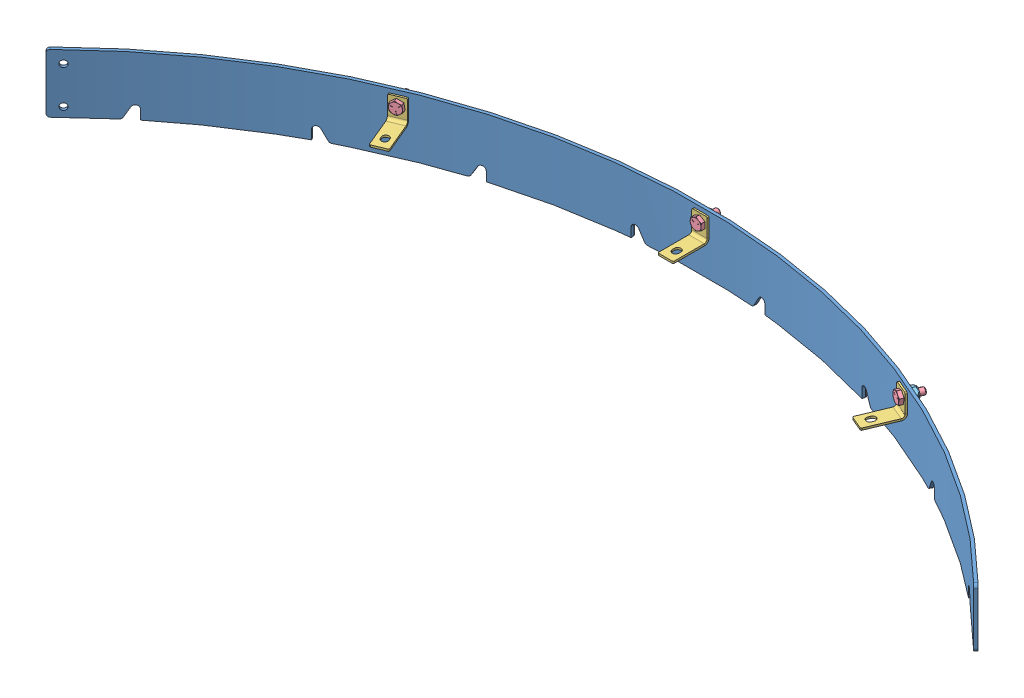
SolidWorks assembly GE-22420, configuration Alt. Lengths in mm.
Overall size (957 60.34 213.8).
14 component instances, 5 part files, 49 mates.
Components (placement in the parent):
- GE-22421-1: GE-22421 [Default] at origin
- tape_VISIONTARGET-1: tape_VISIONTARGET [Default] x (0.630073 0 0.776536) z (-0.776536 0 0.630073)
- tape_VISIONTARGET-2: tape_VISIONTARGET [Default] x (0.285774 0 0.958297) z (-0.958297 0 0.285774)
- tape_VISIONTARGET-3: tape_VISIONTARGET [Default] x (-0.101843 0 0.9948) z (-0.9948 0 -0.101843)
- tape_VISIONTARGET-4: tape_VISIONTARGET [Default] x (-0.474023 0 0.880512) z (-0.880512 0 -0.474023)
- GE-22422-1: GE-22422 [Default] at (-265.7747 33.7439 -617.9649) x (0.92324 0 -0.384223) z (0.384223 0 0.92324)
- GE-22422-2: GE-22422 [Default] at (-7.9375 33.7439 -672.6469) x (1 0 0) z (0 0 1)
- GE-22422-3: GE-22422 [Default] at (251.1183 33.7439 -624.0645) x (0.92324 0 0.384223) z (-0.384223 0 0.92324)
- hex_.25_20_0.75-1: hex_.25_20_0.75 [Default] at (261.3438 47.625 -627.9765) x (0.384223 0 -0.92324) z (0.569796 0.78683 0.237131)
- nylock_.25_20-1: nylock_.25_20 [Default] at (260.4505 47.625 -625.83) x (0.908619 -0.177267 0.378138) z (0.16366 0.984163 0.06811)
- hex_.25_20_0.75-2: hex_.25_20_0.75 [Default] at (0 47.625 -680.1875) x (0 0 -1) z (0.514136 0.857709 0)
- nylock_.25_20-2: nylock_.25_20 [Default] at (0 47.625 -677.8625) x (0.998592 -0.053043 0) z (0.053043 0.998592 0)
- hex_.25_20_0.75-4: hex_.25_20_0.75 [Default] at (-261.3438 47.625 -627.9765) x (-0.384223 0 -0.92324) z (0.341542 0.929056 -0.142139)
- nylock_.25_20-4: nylock_.25_20 [Default] at (-260.4504 47.625 -625.83) x (0.917862 0.107779 -0.381985) z (-0.099506 0.994175 0.041411)
Mates (geometry in assembly coordinates):
- Concentric2: concentric anti-aligned: cylinder of GE-22421-1 through (0 -1034.6728 0) axis (0 1 0) radius 677.8625; cylinder of visionTapeforRing_exoV4-1 through (0 0 0) axis (0 -1 0) radius 677.8625
- Coincident1: coincident aligned: plane of visionRing_exoV4-1 through (0 0 0) normal (0 -1 0); plane of visionTapeforRing_exoV4-1 through (0 0 0) normal (0 -1 0)
- Concentric3: concentric anti-aligned: cylinder of GE-22421-1 through (0 -1034.6728 0) axis (0 1 0) radius 677.8625; cylinder of visionTapeforRing_exoV4-2 through (0 0 0) axis (0 -1 0) radius 677.8625
- Coincident2: coincident aligned: plane of visionRing_exoV4-1 through (0 0 0) normal (0 -1 0); plane of visionTapeforRing_exoV4-2 through (0 0 0) normal (0 -1 0)
- Concentric5: concentric anti-aligned: cylinder of GE-22421-1 through (0 -1034.6728 0) axis (0 1 0) radius 677.8625; cylinder of tape_VISIONTARGET-3 through (0 0 0) axis (0 -1 0) radius 677.8625
- Coincident3: coincident aligned: plane of visionRing_exoV4-1 through (0 0 0) normal (0 -1 0); plane of tape_VISIONTARGET-3 through (0 0 0) normal (0 -1 0)
- Concentric6: concentric anti-aligned: cylinder of GE-22421-1 through (0 -1034.6728 0) axis (0 1 0) radius 677.8625; cylinder of tape_VISIONTARGET-4 through (0 0 0) axis (0 -1 0) radius 677.8625
- Coincident4: coincident aligned: plane of visionRing_exoV4-1 through (0 0 0) normal (0 -1 0); plane of tape_VISIONTARGET-4 through (0 0 0) normal (0 -1 0)
- Coincident5: coincident aligned: plane of GE-22421-1 through (0 0 0) normal (0 0 1)
- Coincident6: coincident aligned: plane of GE-22421-1 through (0 0 0) normal (1 0 0)
- Coincident7: coincident aligned: plane of GE-22421-1 through (0 0 0) normal (0 1 0)
- Coincident8: coincident: line of GE-22421-1 through (-427.1031 9.525 -526.3843) axis (0 -1 0); plane of visionTapeforRing_exoV4-1 through (-427.1031 25.4 -526.3843) normal (-0.776536 0 0.630073)
- Coincident9: coincident: line of GE-22421-1 through (-193.7153 9.525 -649.5937) axis (0 -1 0); plane of visionTapeforRing_exoV4-2 through (-193.7153 25.4 -649.5937) normal (-0.958297 0 0.285774)
- Coincident10: coincident: line of GE-22421-1 through (69.0358 9.525 -674.3379) axis (0 -1 0); plane of tape_VISIONTARGET-3 through (69.0358 25.4 -674.3379) normal (-0.9948 0 -0.101843)
- Coincident11: coincident: line of GE-22421-1 through (321.3225 9.525 -596.8663) axis (0 -1 0); plane of tape_VISIONTARGET-4 through (321.3225 25.4 -596.8663) normal (-0.880512 0 -0.474023)
- Concentric10: concentric anti-aligned: line of GE-22421-1 through (260.4472 47.625 -625.8221) axis (-0.384223 0 0.92324); cylinder of GE-22422-3 through (259.2126 47.625 -622.8556) axis (0.384223 0 -0.92324) radius 3.3782
- Concentric7: concentric anti-aligned: line of GE-22421-1 through (0 47.625 -677.854) axis (0 0 1); cylinder of GE-22422-2 through (0 47.625 -674.6408) axis (0 0 -1) radius 3.3782
- Concentric9: concentric anti-aligned: line of GE-22421-1 through (-260.4472 47.625 -625.8222) axis (0.384223 0 0.92324); cylinder of GE-22422-1 through (-259.2126 47.625 -622.8556) axis (-0.384223 0 -0.92324) radius 3.3782
- Parallel1: parallel anti-aligned: plane of GE-22422-3 through (252.3557 31.75 -585.7208) normal (0 -1 0)
- Coincident15: coincident aligned: plane of GE-22422-2 through (7.9375 31.75 -637.7219) normal (0 -1 0); plane of GE-22422-3 through (252.3557 31.75 -585.7208) normal (0 -1 0)
- Coincident16: coincident aligned: plane of GE-22422-1 through (-237.6993 31.75 -591.8203) normal (0 -1 0); plane of GE-22422-3 through (252.3557 31.75 -585.7208) normal (0 -1 0)
- Coincident17: coincident: cylinder of GE-22421-1 through (0 -1034.6728 0) axis (0 1 0) radius 674.6875; line of GE-22422-3 through (266.5408 36.7347 -619.8058) axis (0 1 0)
- Coincident18: coincident: cylinder of GE-22421-1 through (0 -1034.6728 0) axis (0 1 0) radius 674.6875; line of GE-22422-2 through (7.9375 36.7347 -674.6408) axis (0 1 0)
- Coincident19: coincident: cylinder of GE-22421-1 through (0 -1034.6728 0) axis (0 1 0) radius 674.6875; line of GE-22422-1 through (-251.8844 36.7347 -625.9053) axis (0 1 0)
- Concentric11: concentric aligned: cylinder of GE-22422-3 through (259.2126 47.625 -622.8556) axis (0.384223 0 -0.92324) radius 3.3782; cylinder of hex_.25_20_0.75-1 through (258.4465 47.625 -621.0147) axis (0.384223 0 -0.92324) radius 3.175
- Coincident20: coincident anti-aligned: plane of GE-22422-3 through (265.7747 33.7439 -617.9649) normal (-0.384223 0 0.92324); plane of hex_.25_20_0.75-1 through (259.2821 53.9766 -620.667) normal (0.384223 0 -0.92324)
- Concentric12: concentric aligned: cylinder of hex_.25_20_0.75-1 through (258.4465 47.625 -621.0147) axis (0.384223 0 -0.92324) radius 3.175; cylinder of nylock_.25_20-1 through (260.4505 47.625 -625.83) axis (0.384223 0 -0.92324) radius 3.175
- Tangent1: tangent anti-aligned: cylinder of GE-22421-1 through (0 -1034.6728 0) axis (0 1 0) radius 677.8625; plane of nylock_.25_20-1 through (260.4505 47.625 -625.83) normal (-0.384223 0 0.92324)
- Concentric13: concentric aligned: cylinder of hex_.25_20_0.75-2 through (0 47.625 -672.6469) axis (0 0 -1) radius 3.175; cylinder of nylock_.25_20-2 through (0 47.625 -677.8625) axis (0 0 -1) radius 3.175
- Concentric14: concentric aligned: cylinder of GE-22422-2 through (0 47.625 -674.6408) axis (0 0 -1) radius 3.3782; cylinder of hex_.25_20_0.75-2 through (0 47.625 -672.6469) axis (0 0 -1) radius 3.175
- Coincident21: coincident anti-aligned: plane of GE-22422-2 through (7.9375 33.7439 -672.6469) normal (0 0 1); plane of hex_.25_20_0.75-2 through (0.1052 54.0399 -672.6469) normal (0 0 -1)
- Tangent2: tangent anti-aligned: cylinder of GE-22421-1 through (0 -1034.6728 0) axis (0 1 0) radius 677.8625; plane of nylock_.25_20-2 through (0 47.625 -677.8625) normal (0 0 1)
- Concentric16: concentric aligned: cylinder of hex_.25_20_0.75-4 through (-258.4465 47.625 -621.0147) axis (-0.384223 0 -0.92324) radius 3.175; cylinder of nylock_.25_20-4 through (-260.4504 47.625 -625.83) axis (-0.384223 0 -0.92324) radius 3.175
- Concentric17: concentric aligned: cylinder of GE-22422-1 through (-259.2126 47.625 -622.8556) axis (-0.384223 0 -0.92324) radius 3.3782; cylinder of hex_.25_20_0.75-4 through (-258.4465 47.625 -621.0147) axis (-0.384223 0 -0.92324) radius 3.175
- Coincident22: coincident anti-aligned: plane of GE-22422-1 through (-251.1183 33.7439 -624.0645) normal (0.384223 0 0.92324); plane of hex_.25_20_0.75-4 through (-259.3003 53.9738 -620.6594) normal (-0.384223 0 -0.92324)
- Tangent3: tangent anti-aligned: cylinder of GE-22421-1 through (0 -1034.6728 0) axis (0 1 0) radius 677.8625; plane of nylock_.25_20-4 through (-260.4504 47.625 -625.83) normal (0.384223 0 0.92324)
- Coincident27: coincident anti-aligned: plane of GE-22421-1 through (-103.0944 30.1625 -854.2498) normal (-0.705882 0 -0.708329); plane of visionTapeforRing_exoV4-1 through (-384.6156 25.4 -573.701) normal (0.705882 0 0.708329)
- Coincident28: coincident anti-aligned: plane of GE-22421-1 through (-103.0944 30.1625 -854.2498) normal (-0.705882 0 -0.708329); plane of visionTapeforRing_exoV4-2 through (-196.9172 25.4 -760.751) normal (0.705882 0 0.708329)
- Coincident29: coincident anti-aligned: plane of GE-22421-1 through (-103.0944 30.1625 -854.2498) normal (-0.705882 0 -0.708329); plane of visionTapeforRing_exoV4-3 through (-9.2189 25.4 -947.8011) normal (0.705882 0 0.708329)
- Coincident30: coincident anti-aligned: plane of GE-22421-1 through (-103.0944 30.1625 -854.2498) normal (-0.705882 0 -0.708329); plane of visionTapeforRing_exoV4-4 through (178.4795 25.4 -1134.8511) normal (0.705882 0 0.708329)
- Concentric19: concentric anti-aligned: cylinder of GE-22421-1 through (-290.8852 47.625 -664.8665) axis (0.705882 0 0.708329) radius 3.3782; cylinder of hex_.25_20_0.75-4 through (-288.3571 47.625 -662.3297) axis (-0.705882 0 -0.708329) radius 3.175
- Concentric20: concentric anti-aligned: cylinder of GE-22421-1 through (-101.9738 47.625 -853.1253) axis (0.705882 0 0.708329) radius 3.3782; cylinder of hex_.25_20_0.75-2 through (-99.4457 47.625 -850.5885) axis (-0.705882 0 -0.708329) radius 3.175
- Concentric21: concentric anti-aligned: cylinder of GE-22421-1 through (86.9376 47.625 -1041.3842) axis (0.705882 0 0.708329) radius 3.3782; cylinder of hex_.25_20_0.75-1 through (89.4656 47.625 -1038.8474) axis (-0.705882 0 -0.708329) radius 3.175
- Coincident31: coincident anti-aligned: plane of GE-22421-1 through (-100.8532 30.1625 -852.0009) normal (0.705882 0 0.708329); plane of GE-22422-3 through (93.6805 33.7439 -1045.8626) normal (-0.705882 0 -0.708329)
- Coincident32: coincident anti-aligned: plane of GE-22421-1 through (-100.8532 30.1625 -852.0009) normal (0.705882 0 0.708329); plane of GE-22422-2 through (-95.2308 33.7439 -857.6038) normal (-0.705882 0 -0.708329)
- Coincident33: coincident anti-aligned: plane of GE-22421-1 through (-100.8532 30.1625 -852.0009) normal (0.705882 0 0.708329); plane of GE-22422-1 through (-284.1422 33.7439 -669.345) normal (-0.705882 0 -0.708329)
- Coincident34: coincident anti-aligned: plane of GE-22421-1 through (-103.0944 30.1625 -854.2498) normal (-0.705882 0 -0.708329); plane of nylock_.25_20-4 through (-292.0058 47.625 -665.991) normal (0.705882 0 0.708329)
- Coincident35: coincident anti-aligned: plane of GE-22421-1 through (-103.0944 30.1625 -854.2498) normal (-0.705882 0 -0.708329); plane of nylock_.25_20-2 through (-103.0944 47.625 -854.2498) normal (0.705882 0 0.708329)
- Coincident36: coincident anti-aligned: plane of GE-22421-1 through (-103.0944 30.1625 -854.2498) normal (-0.705882 0 -0.708329); plane of nylock_.25_20-1 through (85.817 47.625 -1042.5086) normal (0.705882 0 0.708329)
